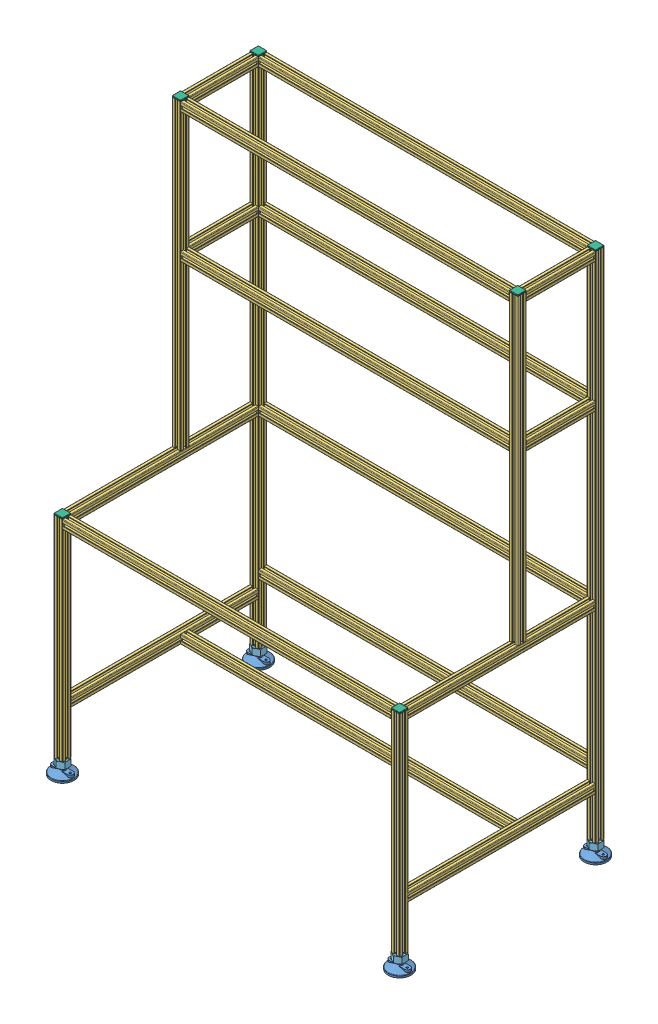
SolidWorks assembly AL-3 Рабочий стол малый с двумя полками, configuration По умолчанию. Lengths in mm.
Overall size (1249 1834.2 759).
74 component instances, 6 part files, 76 mates.
Components (placement in the parent):
- AL-340.010BA.01 Опора D80 с противоскользящей вставкой-8: AL-340.010BA.01 Опора D80 с противоскользящей вставкой [Default] x (0 0 1) z (1 0 0) size (79 18 79)
- AL-1Y12.A42A.01 Шпилька к опоре М8х80-1: AL-1Y12.A42A.01 Шпилька к опоре М8х80 [Default] x (0.999247 0 0.038788) z (0.038788 0 -0.999247) size (15 105.5 18.13)
- AL-3-PS-3030.001 Профиль-2: AL-3-PS-3030.001 Профиль [Default] at (0 1765 255) size (30 30 240)
- AL-3-PS-3030.001 Профиль-6: AL-3-PS-3030.001 Профиль [Default] at (-1170 1765 255) size (30 30 240)
- AL-3-PS-3030.001 Профиль-7: AL-3-PS-3030.001 Профиль [-01] at (0 715 665) x (0 1 0) z (0 0 1) size (30 30 650)
- AL-3-PS-3030.001 Профиль-8: AL-3-PS-3030.001 Профиль [-01] at (-1170 715 665) x (0 1 0) z (0 0 1) size (30 30 650)
- AL-3-PS-3030.001 Профиль-9: AL-3-PS-3030.001 Профиль [-01] at (0 165 665) size (30 30 650)
- AL-3-PS-3030.001 Профиль-10: AL-3-PS-3030.001 Профиль [-01] at (-1170 165 665) size (30 30 650)
- AL-3-PS-3030.001 Профиль-11: AL-3-PS-3030.001 Профиль [-02] at (0 0 680) x (1 0 0) z (0 -1 0) size (30 30 730)
- AL-3-PS-3030.001 Профиль-24: AL-3-PS-3030.001 Профиль [-03] at (0 730 270) x (0 0 1) z (0 -1 0) size (30 30 1050)
- AL-3-PS-3030.001 Профиль-12: AL-3-PS-3030.001 Профиль [-02] at (-1170 0 680) x (1 0 0) z (0 -1 0) size (30 30 730)
- AL-3-PS-3030.001 Профиль-16: AL-3-PS-3030.001 Профиль [-04] at (-1155 1765 270) x (0 0 1) z (-1 0 0) size (30 30 1140)
- AL-3-PS-3030.001 Профиль-17: AL-3-PS-3030.001 Профиль [-04] at (-1155 715 680) x (0 0 1) z (-1 0 0) size (30 30 1140)
- AL-3-PS-3030.001 Профиль-18: AL-3-PS-3030.001 Профиль [-04] at (-1155 715 0) x (0 0 1) z (-1 0 0) size (30 30 1140)
- AL-3-PS-3030.001 Профиль-19: AL-3-PS-3030.001 Профиль [-04] at (-1155 225 0) x (0 0 1) z (-1 0 0) size (30 30 1140)
- AL-3-PS-3030.001 Профиль-20: AL-3-PS-3030.001 Профиль [-04] at (-1155 1765 0) x (0 0 1) z (-1 0 0) size (30 30 1140)
- AL-3-PS-3030.001 Профиль-21: AL-3-PS-3030.001 Профиль [-04] at (-1155 165 270) x (0 0 1) z (-1 0 0) size (30 30 1140)
- AL-3-PS-3030.001 Профиль-22: AL-3-PS-3030.001 Профиль [-05] x (1 0 0) z (0 -1 0) size (30 30 1780)
- AL-3-PS-3030.001 Профиль-23: AL-3-PS-3030.001 Профиль [-05] at (-1170 0 0) x (1 0 0) z (0 -1 0) size (30 30 1780)
- AL-340.010BA.01 Опора D80 с противоскользящей вставкой-9: AL-340.010BA.01 Опора D80 с противоскользящей вставкой [Default] at (-1170 0 0) x (0 0 1) z (1 0 0) size (79 18 79)
- AL-340.010BA.01 Опора D80 с противоскользящей вставкой-10: AL-340.010BA.01 Опора D80 с противоскользящей вставкой [Default] at (0 0 680) x (0 0 1) z (1 0 0) size (79 18 79)
- AL-340.010BA.01 Опора D80 с противоскользящей вставкой-11: AL-340.010BA.01 Опора D80 с противоскользящей вставкой [Default] at (-1170 0 680) x (0 0 1) z (1 0 0) size (79 18 79)
- AL-1Y12.A42A.01 Шпилька к опоре М8х80-2: AL-1Y12.A42A.01 Шпилька к опоре М8х80 [Default] at (-1170 0 0) x (0.999247 0 0.038788) z (0.038788 0 -0.999247) size (15 105.5 18.13)
- AL-1Y12.A42A.01 Шпилька к опоре М8х80-3: AL-1Y12.A42A.01 Шпилька к опоре М8х80 [Default] at (0 0 680) x (0.999247 0 0.038788) z (0.038788 0 -0.999247) size (15 105.5 18.13)
- AL-1Y12.A42A.01 Шпилька к опоре М8х80-4: AL-1Y12.A42A.01 Шпилька к опоре М8х80 [Default] at (-1170 0 680) x (0.999247 0 0.038788) z (0.038788 0 -0.999247) size (15 105.5 18.13)
- AL-3-PS-3030.001 Профиль-25: AL-3-PS-3030.001 Профиль [-03] at (-1170 730 270) x (0 0 1) z (0 -1 0) size (30 30 1050)
- AL-3-PS-3030.001 Профиль-26: AL-3-PS-3030.001 Профиль [-04] at (-1155 1315 0) x (0 0 1) z (-1 0 0) size (30 30 1140)
- AL-3-PS-3030.001 Профиль-27: AL-3-PS-3030.001 Профиль [Default] at (-1170 1315 255) size (30 30 240)
- AL-3-PS-3030.001 Профиль-28: AL-3-PS-3030.001 Профиль [-04] at (-1155 1315 270) x (0 0 1) z (-1 0 0) size (30 30 1140)
- AL-3-PS-3030.001 Профиль-29: AL-3-PS-3030.001 Профиль [Default] at (0 1315 255) size (30 30 240)
- socket button head screw_iso-1: socket button head screw_iso [ISO 7380 - M3 x 6 - 6N] at (0 165 668.85) x (0 0 -1) z (1 0 0) size (7.65 5.7 5.7)
- socket button head screw_iso-2: socket button head screw_iso [ISO 7380 - M3 x 6 - 6N] at (0 715 11.15) x (0 0 1) z (-1 0 0) size (7.65 5.7 5.7)
- socket button head screw_iso-3: socket button head screw_iso [ISO 7380 - M3 x 6 - 6N] at (0 1315 258.85) x (0 0 -1) z (1 0 0) size (7.65 5.7 5.7)
- socket button head screw_iso-4: socket button head screw_iso [ISO 7380 - M3 x 6 - 6N] at (0 1765 258.85) x (0 0 -1) z (1 0 0) size (7.65 5.7 5.7)
- socket button head screw_iso-5: socket button head screw_iso [ISO 7380 - M3 x 6 - 6N] at (-11.15 1315 270) x (-1 0 0) z (0 0.924225 0.381849) size (7.65 5.7 5.7)
- socket button head screw_iso-7: socket button head screw_iso [ISO 7380 - M3 x 6 - 6N] at (-11.15 1765 0) x (-1 0 0) z (0 -0.924225 -0.381849) size (7.65 5.7 5.7)
- socket button head screw_iso-8: socket button head screw_iso [ISO 7380 - M3 x 6 - 6N] at (0 1315 11.15) x (0 0 1) z (-1 0 0) size (7.65 5.7 5.7)
- socket button head screw_iso-9: socket button head screw_iso [ISO 7380 - M3 x 6 - 6N] at (-11.15 715 0) x (-1 0 0) z (0 -0.924225 -0.381849) size (7.65 5.7 5.7)
- socket button head screw_iso-10: socket button head screw_iso [ISO 7380 - M3 x 6 - 6N] at (-11.15 225 0) x (-1 0 0) z (0 -0.924225 -0.381849) size (7.65 5.7 5.7)
- socket button head screw_iso-11: socket button head screw_iso [ISO 7380 - M3 x 6 - 6N] at (0 165 11.15) x (0 0 1) z (-1 0 0) size (7.65 5.7 5.7)
- socket button head screw_iso-12: socket button head screw_iso [ISO 7380 - M3 x 6 - 6N] at (-8.3162 165 270) x (-1 0 0) z (0 0.92365 0.383238) size (7.65 5.7 5.7)
- socket button head screw_iso-13: socket button head screw_iso [ISO 7380 - M3 x 6 - 6N] at (0 726.15 270) x (0 1 0) z (0 0 1) size (7.65 5.7 5.7)
- socket button head screw_iso-14: socket button head screw_iso [ISO 7380 - M3 x 6 - 6N] at (-11.15 1765 270) x (-1 0 0) z (0 0 -1) size (7.65 5.7 5.7)
- socket button head screw_iso-15: socket button head screw_iso [ISO 7380 - M3 x 6 - 6N] at (-11.15 1315 0) x (-1 0 0) z (0 0 -1) size (7.65 5.7 5.7)
- socket button head screw_iso-16: socket button head screw_iso [ISO 7380 - M3 x 6 - 6N] at (0 1765 11.15) x (0 0 1) z (-0.381849 -0.924225 0) size (7.65 5.7 5.7)
- socket button head screw_iso-17: socket button head screw_iso [ISO 7380 - M3 x 6 - 6N] at (-11.15 715 680) x (-1 0 0) z (0 0 -1) size (7.65 5.7 5.7)
- socket button head screw_iso-18: socket button head screw_iso [ISO 7380 - M3 x 6 - 6N] at (0 715 668.85) x (0 0 -1) z (1 0 0) size (7.65 5.7 5.7)
- hex nut gradec_din-1: hex nut gradec_din [PreviewCfg] at (0 -22.5298 0) x (1 0 0) z (0 -1 0) size (38.1 43.99 22.53)
- hex nut gradec_din-2: hex nut gradec_din [PreviewCfg] at (-1170 -22.5298 0) x (1 0 0) z (0 -1 0) size (38.1 43.99 22.53)
- hex nut gradec_din-3: hex nut gradec_din [PreviewCfg] at (0 -22.5298 680) x (1 0 0) z (0 -1 0) size (38.1 43.99 22.53)
- hex nut gradec_din-4: hex nut gradec_din [PreviewCfg] at (-1170 -22.5298 680) x (1 0 0) z (0 -1 0) size (38.1 43.99 22.53)
- socket button head screw_iso-36: socket button head screw_iso [ISO 7380 - M3 x 6 - 6N] at (-1170 715 668.85) x (0 0 -1) z (1 0 0) size (7.65 5.7 5.7)
- socket button head screw_iso-37: socket button head screw_iso [ISO 7380 - M3 x 6 - 6N] at (-1158.85 715 680) size (7.65 5.7 5.7)
- socket button head screw_iso-38: socket button head screw_iso [ISO 7380 - M3 x 6 - 6N] at (-1170 715 11.15) x (0 0 1) z (-1 0 0) size (7.65 5.7 5.7)
- socket button head screw_iso-39: socket button head screw_iso [ISO 7380 - M3 x 6 - 6N] at (-1170 1315 258.85) x (0 0 -1) z (1 0 0) size (7.65 5.7 5.7)
- socket button head screw_iso-40: socket button head screw_iso [ISO 7380 - M3 x 6 - 6N] at (-1170 1765 258.85) x (0 0 -1) z (1 0 0) size (7.65 5.7 5.7)
- socket button head screw_iso-41: socket button head screw_iso [ISO 7380 - M3 x 6 - 6N] at (-1158.85 1765 0) x (1 0 0) z (0 0.924225 0.381849) size (7.65 5.7 5.7)
- socket button head screw_iso-42: socket button head screw_iso [ISO 7380 - M3 x 6 - 6N] at (-1170 1315 11.15) x (0 0 1) z (-1 0 0) size (7.65 5.7 5.7)
- socket button head screw_iso-43: socket button head screw_iso [ISO 7380 - M3 x 6 - 6N] at (-1158.85 715 0) x (1 0 0) z (0 0.924225 0.381849) size (7.65 5.7 5.7)
- socket button head screw_iso-44: socket button head screw_iso [ISO 7380 - M3 x 6 - 6N] at (-1158.85 225 0) x (1 0 0) z (0 0.924225 0.381849) size (7.65 5.7 5.7)
- socket button head screw_iso-45: socket button head screw_iso [ISO 7380 - M3 x 6 - 6N] at (-1170 165 11.15) x (0 0 1) z (-1 0 0) size (7.65 5.7 5.7)
- socket button head screw_iso-46: socket button head screw_iso [ISO 7380 - M3 x 6 - 6N] at (-1161.6838 165 270) x (1 0 0) z (0 -0.92365 -0.383238) size (7.65 5.7 5.7)
- socket button head screw_iso-47: socket button head screw_iso [ISO 7380 - M3 x 6 - 6N] at (-1158.85 1765 270) size (7.65 5.7 5.7)
- socket button head screw_iso-48: socket button head screw_iso [ISO 7380 - M3 x 6 - 6N] at (-1158.85 1315 0) size (7.65 5.7 5.7)
- socket button head screw_iso-49: socket button head screw_iso [ISO 7380 - M3 x 6 - 6N] at (-1170 726.15 270) x (0 1 0) z (0 0 -1) size (7.65 5.7 5.7)
- socket button head screw_iso-50: socket button head screw_iso [ISO 7380 - M3 x 6 - 6N] at (-1158.85 1315 270) x (1 0 0) z (0 -0.924225 -0.381849) size (7.65 5.7 5.7)
- socket button head screw_iso-51: socket button head screw_iso [ISO 7380 - M3 x 6 - 6N] at (-1170 1765 11.15) x (0 0 1) z (-0.381849 0.924225 0) size (7.65 5.7 5.7)
- socket button head screw_iso-52: socket button head screw_iso [ISO 7380 - M3 x 6 - 6N] at (-1170 165 668.85) x (0 0 -1) z (1 0 0) size (7.65 5.7 5.7)
- AL-375.0200A.01 Заглушка торцевая 30х30-1: AL-375.0200A.01 Заглушка торцевая 30х30 [По умолчанию] at (-15 1784.2 -15) x (1 0 0) z (0 -1 0) size (30 30 9.2)
- AL-375.0200A.01 Заглушка торцевая 30х30-2: AL-375.0200A.01 Заглушка торцевая 30х30 [По умолчанию] at (-15 1784.2 255) x (1 0 0) z (0 -1 0) size (30 30 9.2)
- AL-375.0200A.01 Заглушка торцевая 30х30-3: AL-375.0200A.01 Заглушка торцевая 30х30 [По умолчанию] at (-15 734.2 665) x (1 0 0) z (0 -1 0) size (30 30 9.2)
- AL-375.0200A.01 Заглушка торцевая 30х30-4: AL-375.0200A.01 Заглушка торцевая 30х30 [По умолчанию] at (-1185 734.2 665) x (1 0 0) z (0 -1 0) size (30 30 9.2)
- AL-375.0200A.01 Заглушка торцевая 30х30-5: AL-375.0200A.01 Заглушка торцевая 30х30 [По умолчанию] at (-1185 1784.2 -15) x (1 0 0) z (0 -1 0) size (30 30 9.2)
- AL-375.0200A.01 Заглушка торцевая 30х30-6: AL-375.0200A.01 Заглушка торцевая 30х30 [По умолчанию] at (-1185 1784.2 255) x (1 0 0) z (0 -1 0) size (30 30 9.2)
Mates (geometry in assembly coordinates):
- Совпадение1: coincident aligned: plane of AL-3-PS-3030.001 Профиль-22 through (0 0 0) normal (0 0 1)
- Совпадение2: coincident anti-aligned: plane of AL-3-PS-3030.001 Профиль-22 through (0 0 0) normal (0 -1 0)
- Совпадение3: coincident aligned: plane of AL-3-PS-3030.001 Профиль-22 through (0 0 0) normal (1 0 0)
- Совпадение4: coincident aligned: plane of AL-3-PS-3030.001 Профиль-22 through (15 1780 13) normal (1 0 0); plane of AL-3-PS-3030.001 Профиль-2 through (15 1778 15) normal (1 0 0)
- Совпадение5: coincident anti-aligned: plane of AL-3-PS-3030.001 Профиль-22 through (4.75 1780 15) normal (0 0 1); plane of AL-3-PS-3030.001 Профиль-2 through (-8.05 1752.4 15) normal (0 0 -1)
- Совпадение6: coincident aligned: plane of AL-3-PS-3030.001 Профиль-22 through (-8.05 1780 -12.6) normal (0 1 0); plane of AL-3-PS-3030.001 Профиль-2 through (-4.75 1780 15) normal (0 1 0)
- Совпадение7: coincident aligned: plane of AL-3-PS-3030.001 Профиль-22 through (15 1780 13) normal (1 0 0); plane of AL-3-PS-3030.001 Профиль-11 through (15 730 667) normal (1 0 0)
- Совпадение8: coincident aligned: plane of AL-3-PS-3030.001 Профиль-22 through (-8.05 0 -12.6) normal (0 -1 0); plane of AL-3-PS-3030.001 Профиль-11 through (-8.05 0 667.4) normal (0 -1 0)
- Совпадение11: coincident anti-aligned: plane of AL-3-PS-3030.001 Профиль-11 through (4.75 730 665) normal (0 0 -1); plane of AL-3-PS-3030.001 Профиль-7 through (12.6 706.95 665) normal (0 0 1)
- Совпадение12: coincident anti-aligned: plane of AL-3-PS-3030.001 Профиль-22 through (4.75 1780 15) normal (0 0 1); plane of AL-3-PS-3030.001 Профиль-7 through (12.6 706.95 15) normal (0 0 -1)
- Расстояние1: distance = 150 mm aligned: plane of AL-3-PS-3030.001 Профиль-9 through (4.75 150 15) normal (0 -1 0); plane of AL-3-PS-3030.001 Профиль-11 through (-8.05 0 667.4) normal (0 -1 0)
- Совпадение15: coincident anti-aligned: plane of AL-3-PS-3030.001 Профиль-11 through (4.75 730 665) normal (0 0 -1); plane of AL-3-PS-3030.001 Профиль-9 through (-8.05 152.4 665) normal (0 0 1)
- Совпадение16: coincident aligned: plane of AL-3-PS-3030.001 Профиль-11 through (-8.05 730 667.4) normal (0 1 0); plane of AL-3-PS-3030.001 Профиль-17 through (-15 730 684.75) normal (0 1 0)
- Совпадение17: coincident aligned: plane of AL-3-PS-3030.001 Профиль-11 through (-4.75 730 695) normal (0 0 1); plane of AL-3-PS-3030.001 Профиль-17 through (-15 728 695) normal (0 0 1)
- Совпадение18: coincident anti-aligned: plane of AL-3-PS-3030.001 Профиль-11 through (-15 730 693) normal (-1 0 0); plane of AL-3-PS-3030.001 Профиль-17 through (-15 702.4 671.95) normal (1 0 0)
- Совпадение19: coincident aligned: plane of AL-3-PS-3030.001 Профиль-17 through (-15 730 684.75) normal (0 1 0); plane of AL-3-PS-3030.001 Профиль-18 through (-15 730 4.75) normal (0 1 0)
- Совпадение20: coincident aligned: plane of AL-3-PS-3030.001 Профиль-23 through (-1165.25 1780 -15) normal (0 0 -1); plane of AL-3-PS-3030.001 Профиль-18 through (-15 728 -15) normal (0 0 -1)
- Совпадение21: coincident aligned: plane of AL-3-PS-3030.001 Профиль-17 through (-1155 702.4 671.95) normal (-1 0 0); plane of AL-3-PS-3030.001 Профиль-18 through (-1155 702.4 -8.05) normal (-1 0 0)
- Совпадение22: coincident aligned: plane of AL-3-PS-3030.001 Профиль-9 through (4.75 180 15) normal (0 1 0); plane of AL-3-PS-3030.001 Профиль-21 through (-15 180 274.75) normal (0 1 0)
- Совпадение23: coincident anti-aligned: plane of AL-3-PS-3030.001 Профиль-9 through (-15 152 15) normal (-1 0 0); plane of AL-3-PS-3030.001 Профиль-21 through (-15 152.4 261.95) normal (1 0 0)
- Расстояние2: distance = 240 mm anti-aligned: plane of AL-3-PS-3030.001 Профиль-21 through (-15 178 255) normal (0 0 -1); plane of AL-3-PS-3030.001 Профиль-22 through (-4.75 1780 15) normal (0 0 1)
- Совпадение26: coincident anti-aligned: plane of AL-3-PS-3030.001 Профиль-2 through (-15 1778 15) normal (-1 0 0); plane of AL-3-PS-3030.001 Профиль-16 through (-15 1752.4 261.95) normal (1 0 0)
- Совпадение27: coincident aligned: plane of AL-3-PS-3030.001 Профиль-2 through (-4.75 1780 15) normal (0 1 0); plane of AL-3-PS-3030.001 Профиль-16 through (-15 1780 274.75) normal (0 1 0)
- Концентричный2: concentric anti-aligned: cylinder of AL-1Y12.A42A.01 Шпилька к опоре М8х80-1 through (0 -18 0) axis (0 1 0) radius 4; cylinder of AL-340.010BA.01 Опора D80 с противоскользящей вставкой-8 through (0 0 0) axis (0 -1 0) radius 39.5
- Концентричный272: concentric anti-aligned: cylinder of AL-3-PS-3030.001 Профиль-22 through (0 1780 0) axis (0 -1 0) radius 3.65; cylinder of AL-1Y12.A42A.01 Шпилька к опоре М8х80-1 through (0 -18 0) axis (0 1 0) radius 4
- Совпадение563: coincident aligned: plane of AL-3-PS-3030.001 Профиль-7 through (-13 730 15) normal (0 1 0); plane of AL-3-PS-3030.001 Профиль-11 through (-8.05 730 667.4) normal (0 1 0)
- Совпадение564: coincident aligned: plane of AL-3-PS-3030.001 Профиль-7 through (15 719.75 15) normal (1 0 0); plane of AL-3-PS-3030.001 Профиль-11 through (15 730 667) normal (1 0 0)
- Совпадение565: coincident aligned: plane of AL-3-PS-3030.001 Профиль-7 through (15 719.75 15) normal (1 0 0); plane of AL-3-PS-3030.001 Профиль-9 through (15 178 15) normal (1 0 0)
- Расстояние4: distance = 300 mm anti-aligned: plane of AL-3-PS-3030.001 Профиль-16 through (-15 1778 285) normal (0 0 1); plane of AL-3-PS-3030.001 Профиль-20 through (-15 1778 -15) normal (0 0 -1)
- Совпадение567: coincident anti-aligned: plane of AL-3-PS-3030.001 Профиль-2 through (-8.05 1752.4 255) normal (0 0 1); plane of AL-3-PS-3030.001 Профиль-24 through (-13 1780 255) normal (0 0 -1)
- Совпадение568: coincident anti-aligned: plane of AL-3-PS-3030.001 Профиль-24 through (-15 1780 274.75) normal (-1 0 0); plane of AL-3-PS-3030.001 Профиль-16 through (-15 1752.4 261.95) normal (1 0 0)
- Совпадение569: coincident aligned: plane of AL-3-PS-3030.001 Профиль-24 through (12.6 1780 261.95) normal (0 1 0); plane of AL-3-PS-3030.001 Профиль-16 through (-15 1780 274.75) normal (0 1 0)
- Совпадение570: coincident anti-aligned: plane of AL-3-PS-3030.001 Профиль-11 through (-4.65 730 667.2) normal (0 0 1); plane of socket button head screw_iso-1 through (0 166.5 667.2) normal (0 0 -1)
- Концентричный273: concentric aligned: circle of AL-3-PS-3030.001 Профиль-9; circle of socket button head screw_iso-1
- Концентричный274: concentric anti-aligned: cylinder of AL-3-PS-3030.001 Профиль-21 through (-15 165 270) axis (-1 0 0) radius 3.65; circle of socket button head screw_iso-12
- Совпадение571: coincident anti-aligned: plane of AL-3-PS-3030.001 Профиль-22 through (4.65 1780 12.8) normal (0 0 -1); plane of socket button head screw_iso-11 through (0 166.5 12.8) normal (0 0 1)
- Концентричный275: concentric anti-aligned: circle of AL-3-PS-3030.001 Профиль-9; circle of socket button head screw_iso-11
- Совпадение572: coincident anti-aligned: plane of AL-3-PS-3030.001 Профиль-22 through (-12.8 1780 8.05) normal (1 0 0); plane of socket button head screw_iso-10 through (-12.8 225.5728 -1.3863) normal (-1 0 0)
- Концентричный276: concentric anti-aligned: cylinder of AL-3-PS-3030.001 Профиль-19 through (-15 225 0) axis (-1 0 0) radius 3.65; circle of socket button head screw_iso-10
- Совпадение573: coincident anti-aligned: plane of AL-3-PS-3030.001 Профиль-22 through (-12.8 1780 8.05) normal (1 0 0); plane of socket button head screw_iso-9 through (-12.8 715.5728 -1.3863) normal (-1 0 0)
- Концентричный277: concentric anti-aligned: cylinder of AL-3-PS-3030.001 Профиль-18 through (-15 715 0) axis (-1 0 0) radius 3.65; circle of socket button head screw_iso-9
- Совпадение574: coincident anti-aligned: plane of AL-3-PS-3030.001 Профиль-22 through (-4.65 1780 12.8) normal (0 0 -1); plane of socket button head screw_iso-2 through (0 716.5 12.8) normal (0 0 1)
- Концентричный278: concentric anti-aligned: cylinder of AL-3-PS-3030.001 Профиль-7 through (0 715 15) axis (0 0 1) radius 3.65; circle of socket button head screw_iso-2
- Совпадение575: coincident anti-aligned: plane of AL-3-PS-3030.001 Профиль-7 through (-8.05 727.8 15) normal (0 -1 0); plane of socket button head screw_iso-13 through (-1.5 727.8 270) normal (0 1 0)
- Концентричный279: concentric aligned: cylinder of AL-3-PS-3030.001 Профиль-24 through (0 1780 270) axis (0 -1 0) radius 3.65; circle of socket button head screw_iso-13
- Совпадение576: coincident anti-aligned: plane of AL-3-PS-3030.001 Профиль-24 through (-12.8 1780 274.65) normal (1 0 0); plane of socket button head screw_iso-5 through (-12.8 1314.4272 271.3863) normal (-1 0 0)
- Концентричный280: concentric anti-aligned: cylinder of AL-3-PS-3030.001 Профиль-28 through (-15 1315 270) axis (-1 0 0) radius 3.65; circle of socket button head screw_iso-5
- Совпадение577: coincident anti-aligned: plane of AL-3-PS-3030.001 Профиль-24 through (-8.05 1780 257.2) normal (0 0 1); plane of socket button head screw_iso-3 through (0 1316.5 257.2) normal (0 0 -1)
- Концентричный281: concentric aligned: cylinder of AL-3-PS-3030.001 Профиль-29 through (0 1315 15) axis (0 0 1) radius 3.65; circle of socket button head screw_iso-3
- Совпадение578: coincident anti-aligned: plane of AL-3-PS-3030.001 Профиль-24 through (-8.05 1780 257.2) normal (0 0 1); plane of socket button head screw_iso-4 through (0 1766.5 257.2) normal (0 0 -1)
- Концентричный282: concentric aligned: cylinder of AL-3-PS-3030.001 Профиль-2 through (0 1765 15) axis (0 0 1) radius 3.65; circle of socket button head screw_iso-4
- Совпадение579: coincident anti-aligned: plane of AL-3-PS-3030.001 Профиль-24 through (-12.8 1780 274.65) normal (1 0 0); plane of socket button head screw_iso-14 through (-12.8 1766.5 270) normal (-1 0 0)
- Концентричный283: concentric anti-aligned: cylinder of AL-3-PS-3030.001 Профиль-16 through (-15 1765 270) axis (-1 0 0) radius 3.65; circle of socket button head screw_iso-14
- Совпадение580: coincident anti-aligned: plane of AL-3-PS-3030.001 Профиль-22 through (-4.65 1780 12.8) normal (0 0 -1); plane of socket button head screw_iso-8 through (0 1316.5 12.8) normal (0 0 1)
- Концентричный284: concentric anti-aligned: cylinder of AL-3-PS-3030.001 Профиль-29 through (0 1315 15) axis (0 0 1) radius 3.65; circle of socket button head screw_iso-8
- Совпадение581: coincident anti-aligned: plane of AL-3-PS-3030.001 Профиль-22 through (-12.8 1780 -8.05) normal (1 0 0); plane of socket button head screw_iso-15 through (-12.8 1316.5 0) normal (-1 0 0)
- Концентричный285: concentric anti-aligned: cylinder of AL-3-PS-3030.001 Профиль-26 through (-15 1315 0) axis (-1 0 0) radius 3.65; circle of socket button head screw_iso-15
- Совпадение582: coincident anti-aligned: plane of AL-3-PS-3030.001 Профиль-22 through (-12.8 1780 8.05) normal (1 0 0); plane of socket button head screw_iso-7 through (-12.8 1765.5728 -1.3863) normal (-1 0 0)
- Концентричный286: concentric anti-aligned: cylinder of AL-3-PS-3030.001 Профиль-20 through (-15 1765 0) axis (-1 0 0) radius 3.65; circle of socket button head screw_iso-7
- Совпадение583: coincident anti-aligned: plane of AL-3-PS-3030.001 Профиль-22 through (-4.65 1780 12.8) normal (0 0 -1); plane of socket button head screw_iso-16 through (-1.3863 1765.5728 12.8) normal (0 0 1)
- Концентричный287: concentric anti-aligned: cylinder of AL-3-PS-3030.001 Профиль-2 through (0 1765 15) axis (0 0 1) radius 3.65; circle of socket button head screw_iso-16
- Совпадение584: coincident anti-aligned: plane of AL-3-PS-3030.001 Профиль-11 through (-12.8 730 688.05) normal (1 0 0); plane of socket button head screw_iso-17 through (-12.8 716.5 680) normal (-1 0 0)
- Концентричный288: concentric anti-aligned: cylinder of AL-3-PS-3030.001 Профиль-17 through (-15 715 680) axis (-1 0 0) radius 3.65; circle of socket button head screw_iso-17
- Совпадение585: coincident anti-aligned: plane of AL-3-PS-3030.001 Профиль-11 through (4.65 730 667.2) normal (0 0 1); plane of socket button head screw_iso-18 through (0 716.5 667.2) normal (0 0 -1)
- Концентричный289: concentric aligned: cylinder of AL-3-PS-3030.001 Профиль-7 through (0 715 15) axis (0 0 1) radius 3.65; cylinder of socket button head screw_iso-18 through (0 715 668.85) axis (0 0 1) radius 1.5
- Концентричный290: concentric anti-aligned: cylinder of AL-1Y12.A42A.01 Шпилька к опоре М8х80-1 through (0 -18 0) axis (0 1 0) radius 4; cylinder of hex nut gradec_din-1 through (0 0 0) axis (0 -1 0) radius 11.1125
- Совпадение586: coincident anti-aligned: plane of AL-3-PS-3030.001 Профиль-22 through (-8.05 0 -12.6) normal (0 -1 0); plane of hex nut gradec_din-1 through (-38.1 0 0) normal (0 1 0)
- Совпадение588: coincident anti-aligned: plane of AL-3-PS-3030.001 Профиль-22 through (-8.05 1780 -12.6) normal (0 1 0); plane of AL-375.0200A.01 Заглушка торцевая 30х30-1 through (3.6986 1780 15) normal (0 -1 0)
- Совпадение589: coincident aligned: plane of AL-3-PS-3030.001 Профиль-22 through (15 1780 -13) normal (1 0 0); plane of AL-375.0200A.01 Заглушка торцевая 30х30-1 through (15 1784.2 -15) normal (1 0 0)
- Совпадение590: coincident aligned: plane of AL-3-PS-3030.001 Профиль-22 through (4.75 1780 -15) normal (0 0 -1); plane of AL-375.0200A.01 Заглушка торцевая 30х30-1 through (-15 1784.2 -15) normal (0 0 -1)
- Совпадение591: coincident anti-aligned: plane of AL-3-PS-3030.001 Профиль-24 through (12.6 1780 261.95) normal (0 1 0); plane of AL-375.0200A.01 Заглушка торцевая 30х30-2 through (3.6986 1780 285) normal (0 -1 0)
- Совпадение592: coincident aligned: plane of AL-3-PS-3030.001 Профиль-24 through (-13 1780 285) normal (0 0 1); plane of AL-375.0200A.01 Заглушка торцевая 30х30-2 through (-15 1784.2 285) normal (0 0 1)
- Совпадение593: coincident aligned: plane of AL-3-PS-3030.001 Профиль-24 through (15 1780 274.75) normal (1 0 0); plane of AL-375.0200A.01 Заглушка торцевая 30х30-2 through (15 1784.2 255) normal (1 0 0)
- Совпадение594: coincident anti-aligned: plane of AL-3-PS-3030.001 Профиль-11 through (-8.05 730 667.4) normal (0 1 0); plane of AL-375.0200A.01 Заглушка торцевая 30х30-3 through (3.6986 730 695) normal (0 -1 0)
- Совпадение595: coincident aligned: plane of AL-3-PS-3030.001 Профиль-11 through (15 730 693) normal (1 0 0); plane of AL-375.0200A.01 Заглушка торцевая 30х30-3 through (15 734.2 665) normal (1 0 0)
- Совпадение596: coincident aligned: plane of AL-3-PS-3030.001 Профиль-11 through (4.75 730 695) normal (0 0 1); plane of AL-375.0200A.01 Заглушка торцевая 30х30-3 through (-15 734.2 695) normal (0 0 1)
